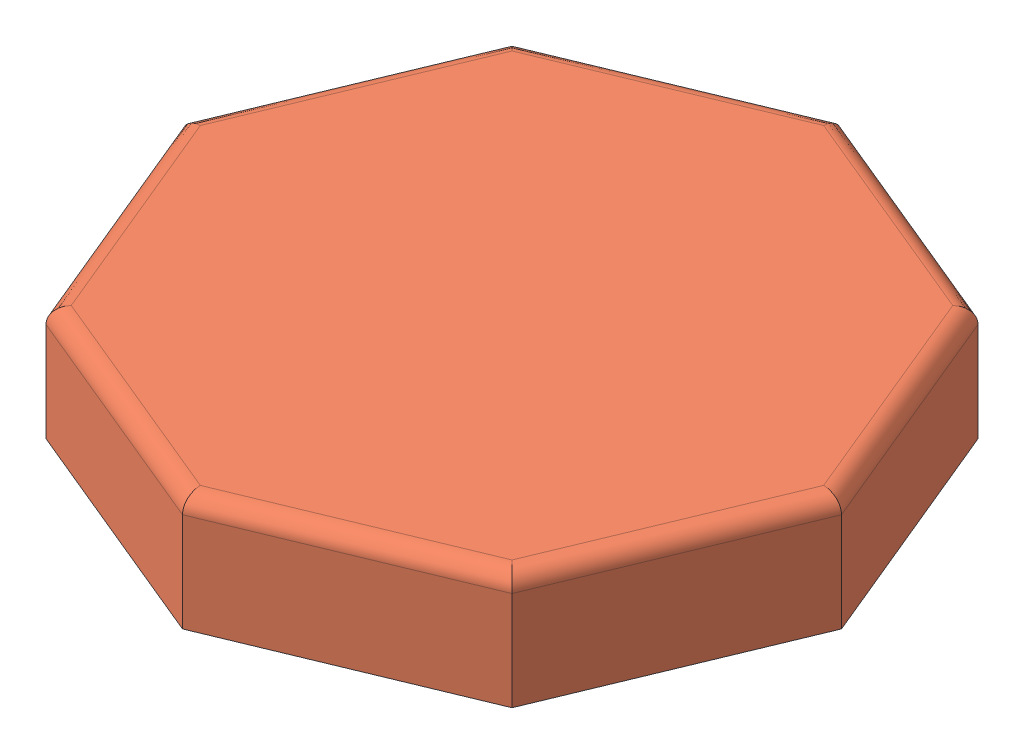
SolidWorks assembly SPYDER_VER_2, configuration Default. Lengths in mm.
Overall size (399.81 90 399.81).
2 component instances, 2 part files, 3 mates.
Components (placement in the parent):
- SP-chassis-1: SP-chassis [Default] at (163.298 278.0074 409.538) x (-1 0 0) z (0 -1 0) size (391.97 391.97 23)
- SP-body-2: SP-body [Default] at (162.9618 275.0074 410.3498) x (0 0 1) z (-1 0 0) size (399.81 90 399.81)
Mates (geometry in assembly coordinates):
- Coincident30: coincident: plane of SP-chassis-1 through (301.88 275.0074 270.9561) normal (0.92388 0 -0.382683); plane of SP-body-2 through (360.0943 345.0074 411.4978) normal (-0.92388 0 0.382683)
- Coincident31: coincident: plane of SP-chassis-1 through (163.298 275.0074 409.538) normal (0 -1 0); plane of SP-body-2 through (162.9618 275.0074 410.3498) normal (0 -1 0)
- Coincident32: coincident: plane of SP-chassis-1 through (24.7161 275.0074 270.9561) normal (-0.382683 0 -0.92388); plane of SP-body-2 through (164.1098 345.0074 213.2173) normal (0.382683 0 0.92388)
